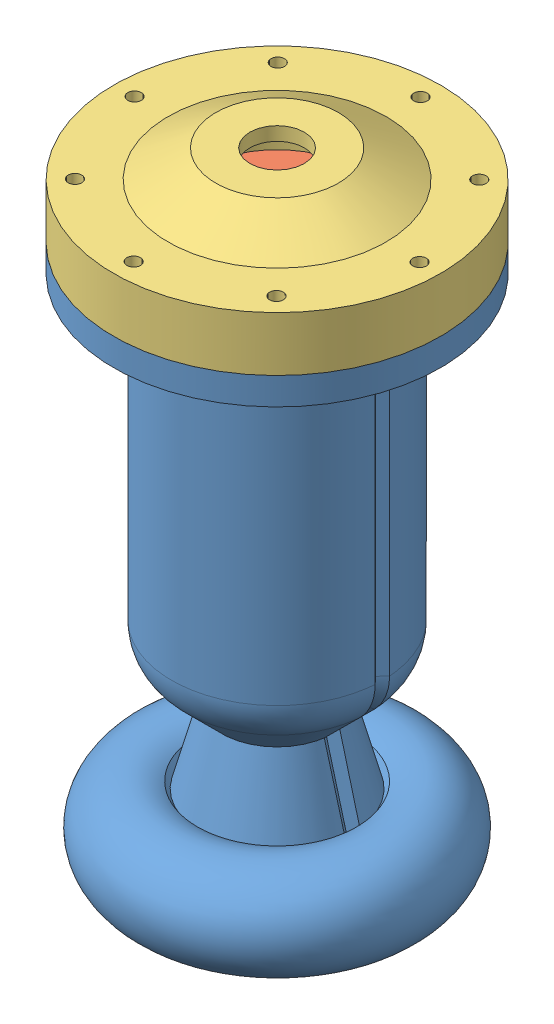
SolidWorks assembly channel cooling jacket engine, configuration Default. Lengths in mm.
Overall size (152.89 296.14 152.89).
3 component instances, 3 part files, 6 mates.
Components (placement in the parent):
- slot cooling jacket 4-1: slot cooling jacket 4 [Default] at origin size (152.4 258.04 152.4)
- impinging injector-1: impinging injector [Default] at (0 -6.35 0) size (82.55 19.05 82.55)
- dome-1: dome [Default] at (0 38.1 0) x (0.999995 0 0.003229) z (-0.003229 0 0.999995) size (152.4 38.1 152.4)
Mates (geometry in assembly coordinates):
- Coincident3: coordinate: point of slot cooling jacket 4-1
- Concentric1: concentric anti-aligned: cylinder of slot cooling jacket 4-1 through (0 0 0) axis (0 -1 0) radius 38.1; cylinder of impinging injector-1 through (0 12.7 0) axis (0 1 0) radius 38.1
- Coincident4: coincident anti-aligned: plane of slot cooling jacket 4-1 through (-38.1 0 0) normal (0 1 0); plane of impinging injector-1 through (-38.1 0 0) normal (0 -1 0)
- Concentric2: concentric aligned: cylinder of slot cooling jacket 4-1 through (0 0 0) axis (0 -1 0) radius 76.2; cylinder of dome-1 through (0 38.1 0) axis (0 -1 0) radius 76.2
- Coincident5: coincident anti-aligned: plane of slot cooling jacket 4-1 through (-49.2125 0 0) normal (0 1 0); plane of dome-1 through (-76.1996 0 -0.2461) normal (0 -1 0)
- Coincident6: coincident aligned: plane of impinging injector-1 through (0 -6.35 0) normal (0 0 1)
